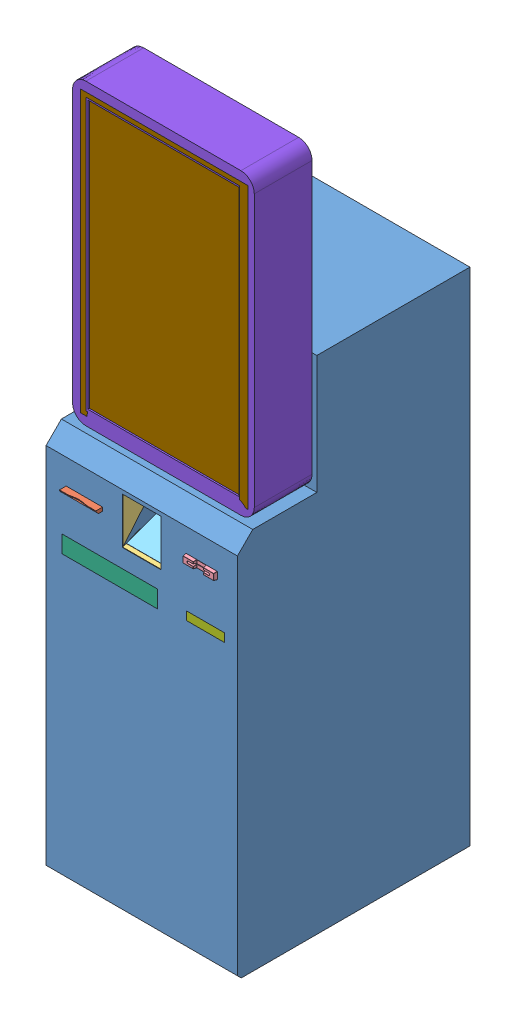
SolidWorks assembly 0StandardConcept32new, configuration Default. Lengths in mm.
Overall size (500 1780 624.98).
9 component instances, 9 part files, 24 mates.
Components (placement in the parent):
- Body-1: Body [Default] at (-208.3287 -13.927 -327.7702) size (500 1310 607.53)
- thermal printer-1: thermal printer [Default] at (-108.3287 819.573 -191.2702) size (132 144.55 271.2)
- POS-In-1: POS-In [Default] at (93.6713 938.073 -128.7702) size (104 123.01 101.61)
- XST card reader PI65C-120-GDS-MFR-1: XST card reader PI65C-120-GDS-MFR [Default] at (198.0454 875.5747 -131.3102) size (101.6 25.4 105.37)
- KeypadMetal-1: KeypadMetal [Default] at (41.6713 847.6632 -220.3257) x (1 0 0) z (0 -0.939693 -0.34202) size (133.3 91.1 23.5)
- DispenserShutter-1: DispenserShutter [Default] at (83.3379 721.867 -137.7702) size (250 45 10)
- AcceptorShutter-1: AcceptorShutter [Default] at (258.3379 733.367 -137.7702) size (100 22 10)
- Screen32-1: Screen32 [Default] at (-155.8287 1026.073 -184.2963) x (-1 0 0) z (0 0 -1) size (475 780 151)
- TouchScreen32inch-1: TouchScreen32inch [Default] at (262.6846 1741.5622 -208.8963) x (0 1 0) z (1 0 0) size (733 113.4 446.1)
Mates (geometry in assembly coordinates):
- Coincident5: coincident aligned: plane of thermal printer-1 through (-108.3287 877.873 -128.7702) normal (0 0 1); plane of assembly through (0 0 -128.7702) normal (0 0 1)
- Parallel2: parallel aligned: plane of Body-1 through (291.6713 986.073 -167.7702) normal (0 1 0); plane of POS-In-1 through (93.6713 938.073 -128.7702) normal (0 1 0)
- Coincident8: coincident aligned: plane of POS-In-1 through (-10.3287 936.073 -128.7702) normal (0 0 1); plane of assembly through (0 0 -128.7702) normal (0 0 1)
- Coincident9: coincident aligned: plane of Body-1 through (-8.3287 936.073 -395.7702) normal (1 0 0); plane of POS-In-1 through (-8.3287 938.073 -128.7702) normal (1 0 0)
- Coincident10: coincident aligned: plane of Body-1 through (-8.3287 936.073 -395.7702) normal (0 -1 0); plane of POS-In-1 through (93.6713 936.073 -128.7702) normal (0 -1 0)
- Coincident11: coincident anti-aligned: plane of Body-1 through (-60.6787 880.573 -395.7702) normal (0 -1 0); plane of thermal printer-1 through (-60.6787 880.573 -128.7702) normal (0 1 0)
- Coincident12: coincident anti-aligned: plane of Body-1 through (-60.6787 880.573 -395.7702) normal (-1 0 0); plane of thermal printer-1 through (-60.6787 871.173 -128.7702) normal (1 0 0)
- Distance1: distance = 1 mm aligned: plane of XST card reader PI65C-120-GDS-MFR-1 through (248.8445 862.8747 -128.7702) normal (0 0 1); plane of Body-1 through (291.6713 -3.927 -127.7702) normal (0 0 1)
- Coincident24: coincident anti-aligned: plane of Body-1 through (239.3213 884.973 -395.7702) normal (-1 0 0); plane of XST card reader PI65C-120-GDS-MFR-1 through (239.3213 866.1763 -128.7702) normal (1 0 0)
- Distance3: distance = 1 mm aligned: plane of KeypadMetal-1 through (41.6713 849.5426 -219.6416) normal (0 0.939693 0.34202); plane of POS-In-1 through (93.6713 831.8818 -168.1953) normal (0 0.939693 0.34202)
- Width6: width anti-aligned: plane of POS-In-1 through (91.6713 938.073 -128.7702) normal (-1 0 0); plane of POS-In-1 through (-8.3287 938.073 -128.7702) normal (1 0 0); plane of KeypadMetal-1 through (100.2713 837.4206 -224.0537) normal (1 0 0); plane of KeypadMetal-1 through (-16.9287 837.4206 -224.0537) normal (-1 0 0)
- Distance4: distance = 10 mm aligned: plane of KeypadMetal-1 through (-6.8287 821.3071 -136.2177) normal (0 -0.34202 0.939693); plane of POS-In-1 through (-7.5921 815.0679 -127.8468) normal (0 -0.34202 0.939693)
- Coincident33: coincident anti-aligned: plane of Body-1 through (156.7813 884.973 -395.7702) normal (0 -1 0); plane of XST card reader PI65C-120-GDS-MFR-1 through (156.7695 884.973 -128.7702) normal (0 1 0)
- Coincident34: coincident aligned: plane of Body-1 through (291.6713 -3.927 -127.7702) normal (0 0 1); plane of DispenserShutter-1 through (83.3379 721.867 -127.7702) normal (0 0 1)
- Coincident35: coincident anti-aligned: plane of Body-1 through (83.3379 766.867 -395.7702) normal (-1 0 0); plane of DispenserShutter-1 through (83.3379 721.867 -127.7702) normal (1 0 0)
- Coincident36: coincident anti-aligned: plane of Body-1 through (-166.6621 766.867 -395.7702) normal (0 -1 0); plane of DispenserShutter-1 through (83.3379 766.867 -127.7702) normal (0 1 0)
- Coincident37: coincident anti-aligned: plane of Body-1 through (158.3379 755.367 -395.7702) normal (0 -1 0); plane of AcceptorShutter-1 through (258.3379 755.367 -127.7702) normal (0 1 0)
- Coincident38: coincident anti-aligned: plane of Body-1 through (258.3379 733.367 -395.7702) normal (-1 0 0); plane of AcceptorShutter-1 through (258.3379 733.367 -127.7702) normal (1 0 0)
- Coincident39: coincident aligned: plane of Body-1 through (291.6713 -3.927 -127.7702) normal (0 0 1); plane of AcceptorShutter-1 through (258.3379 733.367 -127.7702) normal (0 0 1)
- Coincident40: coincident anti-aligned: plane of Body-1 through (291.6713 986.073 -335.2963) normal (0 0 1); plane of Screen32-1 through (-160.8287 1021.073 -335.2963) normal (0 0 -1)
- Coincident41: coincident anti-aligned: plane of Body-1 through (291.6713 986.073 -167.7702) normal (0 1 0); plane of Screen32-1 through (244.1713 986.073 -334.2963) normal (0 -1 0)
- Width7: width anti-aligned: plane of Body-1 through (-208.3287 -13.927 -327.7702) normal (-1 0 0); plane of Body-1 through (291.6713 -13.927 -327.7702) normal (1 0 0); plane of Screen32-1 through (279.1713 1731.073 -334.2963) normal (1 0 0); plane of Screen32-1 through (-195.8287 1731.073 -334.2963) normal (-1 0 0)
- Coincident42: coincident aligned: plane of Screen32-1 through (244.1713 1021.073 -184.2963) normal (0 0 1); plane of TouchScreen32inch-1 through (262.6846 1741.5622 -184.2963) normal (0 0 1)
- Parallel3: parallel anti-aligned: plane of Screen32-1 through (244.1713 1766.073 -334.2963) normal (0 1 0); plane of TouchScreen32inch-1 through (262.6846 1008.5622 -184.2963) normal (0 -1 0)
